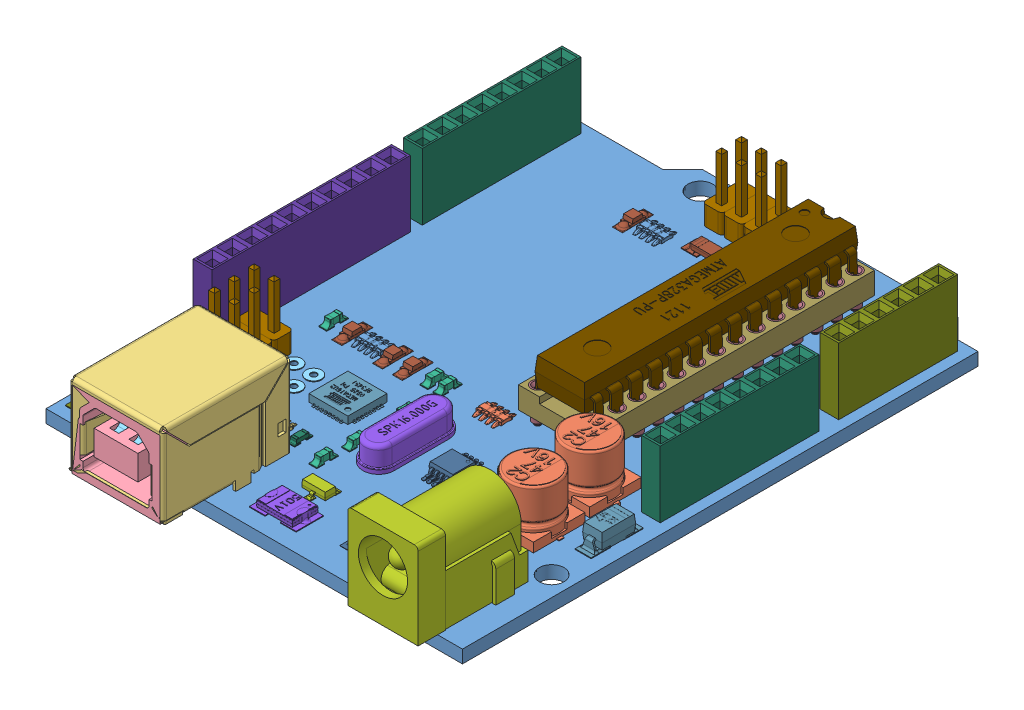
SolidWorks assembly Arduino Uno, configuration Default. Lengths in mm.
Overall size (53.34 15.65 74.93).
87 component instances, 35 part files, 133 mates.
Components (placement in the parent):
- unoboard blue-1: unoboard blue [Default] at origin size (53.34 1.65 68.58)
- 47uf CAP Dcase-1: 47uf CAP Dcase [Défaut] at (-9.4141 0 -18.4991) x (0 0 -1) z (1 0 0) size (6.6 6.6 7.25)
- USB type b-1: USB type b [Default] at (-38.02 0.83 6.35) size (13.72 15.2 16.5)
  - USB SHELL-1: USB SHELL [Default] at origin size (13.72 15.2 16.5)
  - USB core-1: USB core [Défaut] at origin size (11.3 10.68 15.75)
  - usb top contact-1: usb top contact [Default] at (1.25 5.69 0.01) size (1 9.67 13.76)
  - usb btm contact-1: usb btm contact [Default] at (1.25 4.01 -0.69) size (1 6.84 11.76)
  - usb btm contact-2: usb btm contact [Default] at (-1.25 4.01 -0.69) size (1 6.84 11.76)
  - usb top contact-2: usb top contact [Default] at (-1.25 5.69 0.01) size (1 9.67 13.76)
- power jack-1: power jack [Défaut] at (-7.675 0 2.5) size (9.45 15.2 14.2)
- 47uf CAP Dcase-2: 47uf CAP Dcase [Défaut] at (-9.4141 0.3 -25.7132) x (0 0 -1) z (1 0 0) size (6.6 6.6 7.25)
- crystal-1: crystal [Default] at (-26.162 0 -18.923) x (1 0 0) z (0 0 -1) size (4 5 11)
- 2pin_header__02-1: 2pin_header__02 [Default] at (-46.23 0 -15.75) size (5 11.75 2.54)
- nano - reg-1: nano - reg [Default] at (-17.399 0 -7.747) size (6.5 1.69 8.3)
- led 0805-1: led 0805 [Default] at (-34.29 0 -27.94) x (0 0 1) z (-1 0 0) size (4 0.86 1.35)
- 2pin_header__02-2: 2pin_header__02 [Default] at (-30.43 0 -64.91) x (0 0 1) z (-1 0 0) size (5 11.75 2.54)
- dip28-1: dip28 [Default] at (-16.383 1.5 -46.355) x (0 0 -1) z (1 0 0) size (35.48 7.37 10.1)
  - dip28-1: dip28 [Default] at origin size (35.48 2.8 10.1)
  - dip socket pin-1: dip socket pin [Default] at (16.51 2.8 -3.81) size (1.7 7.37 1.7)
  - dip socket pin-2: dip socket pin [Default] at (16.51 2.8 3.81) size (1.7 7.37 1.7)
  - dip socket pin-3: dip socket pin [Default] at (13.97 2.8 -3.81) size (1.7 7.37 1.7)
  - dip socket pin-4: dip socket pin [Default] at (13.97 2.8 3.81) size (1.7 7.37 1.7)
  - dip socket pin-5: dip socket pin [Default] at (11.43 2.8 -3.81) size (1.7 7.37 1.7)
  - dip socket pin-6: dip socket pin [Default] at (11.43 2.8 3.81) size (1.7 7.37 1.7)
  - dip socket pin-7: dip socket pin [Default] at (8.89 2.8 -3.81) size (1.7 7.37 1.7)
  - dip socket pin-8: dip socket pin [Default] at (8.89 2.8 3.81) size (1.7 7.37 1.7)
  - dip socket pin-9: dip socket pin [Default] at (6.35 2.8 -3.81) size (1.7 7.37 1.7)
  - dip socket pin-10: dip socket pin [Default] at (6.35 2.8 3.81) size (1.7 7.37 1.7)
  - dip socket pin-11: dip socket pin [Default] at (3.81 2.8 -3.81) size (1.7 7.37 1.7)
  - dip socket pin-12: dip socket pin [Default] at (3.81 2.8 3.81) size (1.7 7.37 1.7)
  - dip socket pin-13: dip socket pin [Default] at (1.27 2.8 -3.81) size (1.7 7.37 1.7)
  - dip socket pin-14: dip socket pin [Default] at (1.27 2.8 3.81) size (1.7 7.37 1.7)
  - dip socket pin-15: dip socket pin [Default] at (-1.27 2.8 -3.81) size (1.7 7.37 1.7)
  - dip socket pin-16: dip socket pin [Default] at (-1.27 2.8 3.81) size (1.7 7.37 1.7)
  - dip socket pin-17: dip socket pin [Default] at (-3.81 2.8 -3.81) size (1.7 7.37 1.7)
  - dip socket pin-18: dip socket pin [Default] at (-3.81 2.8 3.81) size (1.7 7.37 1.7)
  - dip socket pin-19: dip socket pin [Default] at (-6.35 2.8 -3.81) size (1.7 7.37 1.7)
  - dip socket pin-20: dip socket pin [Default] at (-6.35 2.8 3.81) size (1.7 7.37 1.7)
  - dip socket pin-21: dip socket pin [Default] at (-8.89 2.8 -3.81) size (1.7 7.37 1.7)
  - dip socket pin-22: dip socket pin [Default] at (-8.89 2.8 3.81) size (1.7 7.37 1.7)
  - dip socket pin-23: dip socket pin [Default] at (-11.43 2.8 -3.81) size (1.7 7.37 1.7)
  - dip socket pin-24: dip socket pin [Default] at (-11.43 2.8 3.81) size (1.7 7.37 1.7)
  - dip socket pin-25: dip socket pin [Default] at (-13.97 2.8 -3.81) size (1.7 7.37 1.7)
  - dip socket pin-26: dip socket pin [Default] at (-13.97 2.8 3.81) size (1.7 7.37 1.7)
  - dip socket pin-27: dip socket pin [Default] at (-16.51 2.8 -3.81) size (1.7 7.37 1.7)
  - dip socket pin-28: dip socket pin [Default] at (-16.51 2.8 3.81) size (1.7 7.37 1.7)
- 2pin_header__02-3: 2pin_header__02 [Default] at (-27.89 0 -64.91) x (0 0 1) z (-1 0 0) size (5 11.75 2.54)
- 2pin_header__02-4: 2pin_header__02 [Default] at (-25.35 0 -64.91) x (0 0 1) z (-1 0 0) size (5 11.75 2.54)
- 2pin_header__02-5: 2pin_header__02 [Default] at (-46.23 0 -18.29) size (5 11.75 2.54)
- 2pin_header__02-6: 2pin_header__02 [Default] at (-46.23 0 -20.83) size (5 11.75 2.54)
- atmega16u2-1: atmega16u2 [Default] at (-34.671 0.06 -20) x (1 0 0) z (0 0 -1) size (5.5 1.01 5.5)
- led 0805-2: led 0805 [Default] at (-36.83 0 -27.94) x (0 0 1) z (-1 0 0) size (4 0.86 1.35)
- led 0805-3: led 0805 [Default] at (-42.037 0 -27.94) x (0 0 1) z (-1 0 0) size (4 0.86 1.35)
- led 0805-4: led 0805 [Default] at (-36.576 0 -58.42) x (0 0 1) z (-1 0 0) size (4 0.86 1.35)
- 8 PORT HEADER-3: 8 PORT HEADER [Default] at (-50.8 0 -45.72) x (0 0 -1) z (1 0 0) size (20.32 10.51 2.41)
- 8 PORT HEADER-4: 8 PORT HEADER [Default] at (-2.54 0 -27.94) x (0 0 -1) z (1 0 0) size (20.32 10.51 2.41)
- 6 PORT HEADER-3: 6 PORT HEADER [Default] at (-2.54 0 -50.8) x (0 0 -1) z (1 0 0) size (15.24 10.51 2.41)
- 10 PORT HEADER-1: 10 PORT HEADER [Default] at (-50.8 0 -18.796) x (0 0 -1) z (1 0 0) size (25.4 10.51 2.41)
- ATMEL328P-1: ATMEL328P [Default] at (-16.383 4.3 -46.355) x (0 0 -1) z (1 0 0) size (35 7.27 7.87)
- 102 RESISTOR PACK-1: 102 RESISTOR PACK [Default] at (-33.782 0 -58.42) size (3.2 0.46 3)
- 102 RESISTOR PACK-2: 102 RESISTOR PACK [Default] at (-39.37 0 -27.94) size (3.2 0.46 3)
- 103 RESISTOR PACK-3: 103 RESISTOR PACK [Default] at (-23.876 0 -27.94) size (3.2 0.46 3)
- 220 RESISTOR PACK-1: 220 RESISTOR PACK [Default] at (-36.83 0 -12.827) size (3.2 0.46 3)
- 16mhz crystal - measured-1: 16mhz crystal - measured [Default] at (-24.892 0 -41.275) x (0 0 -1) z (1 0 0) size (3.4 0.8 2)
- PADS001-1: PADS001 [Default] at (-39.878 0.1 -18.288) x (-1 0 0) z (0 0 1) size (4.54 0.1 4.54)
- 603 cap on pad-1: 603 cap on pad [Défaut] at (-44.45 0 -27.94) x (0 0 -1) z (1 0 0) size (2.76 0.91 1.12)
- ssot3-1: ssot3 [Default] at (-26.5 0 -8.128) x (-1 0 0) z (0 0 -1) size (3 1.13 3.09)
- mf-msmf050-2-1: mf-msmf050-2 [Default] at (-26.5 0 -4.064) size (5.77 1.02 3.72)
- 603 cap on pad-2: 603 cap on pad [Défaut] at (-29.845 0 -27.94) x (0 0 -1) z (1 0 0) size (2.76 0.91 1.12)
- 603 cap on pad-3: 603 cap on pad [Défaut] at (-31.496 0 -27.94) x (0 0 -1) z (1 0 0) size (2.76 0.91 1.12)
- SOT23-5-1: SOT23-5 [Default] at (-15.24 0 -21.971) x (0 0 -1) z (1 0 0) size (3.7 1.4 2.9)
- 603 cap on pad-4: 603 cap on pad [Défaut] at (-15.24 0 -18.415) size (2.76 0.91 1.12)
- 603 cap on pad-5: 603 cap on pad [Défaut] at (-29.845 0 -12.065) x (0 0 1) z (-1 0 0) size (2.76 0.91 1.12)
- 603 cap on pad-6: 603 cap on pad [Défaut] at (-29.591 0 -22.352) x (0 0 1) z (-1 0 0) size (2.76 0.91 1.12)
- 603 cap on pad-7: 603 cap on pad [Défaut] at (-29.591 0 -16.002) x (0 0 1) z (-1 0 0) size (2.76 0.91 1.12)
- 603 cap on pad-8: 603 cap on pad [Défaut] at (-41.91 0 -12.7) x (0 0 1) z (-1 0 0) size (2.76 0.91 1.12)
- lp2985dgkr-1: lp2985dgkr [Default] at (-20.32 0 -19.05) x (0 0 -1) z (1 0 0) size (5.85 1.1 3)
- cd1206 diode-1: cd1206 diode [Default] at (-27.94 0 -59.436) x (0 0 -1) z (1 0 0) size (2.07 0.96 5)
- cd1206 diode-2: cd1206 diode [Default] at (-46.228 0 -13.081) x (0 0 1) z (-1 0 0) size (2.07 0.96 5)
- 603 resistor-1: 603 resistor [Default] at (-29.591 0 -19.05) x (0 0 1) z (-1 0 0) size (2.36 0.61 1.03)
- blm21-1: blm21 [Défaut] at (-45.085 0 -7.62) x (0 0 -1) z (1 0 0) size (2.76 0.96 1.33)
- m7 diode-1: m7 diode [Default] at (-2.794 0 -21.59) x (0 0 -1) z (1 0 0) size (6.66 2.35 2.5)
- MLC0603-1: MLC0603 [Default] at (-33.655 0 -12.827) x (0 0 -1) z (1 0 0) size (2.36 0.6 1.03)
- MLC0603-2: MLC0603 [Default] at (-39.37 0 -12.827) x (0 0 -1) z (1 0 0) size (2.36 0.6 1.03)
- RESET BUTTON-1: RESET BUTTON [Default] at (-49.403 0 -6.35) size (6.2 3.1 9.6)
  - RESET CORE-1: RESET CORE [Default] at (0 0.1 0) x (-1 0 0) z (0 0 -1) size (6.2 3.1 9.6)
  - RESET-1: RESET [Default] at (0 0.1 0) x (0 0 1) z (-1 0 0) size (7.3 2 6.2)
Mates (geometry in assembly coordinates):
- Distance1: distance = 2.5 mm aligned: plane of power jack-1 through (-7.675 0 2.5) normal (0 0 1); plane of unoboard blue-1 through (0 0 0) normal (0 0 1)
- Coincident2: coincident aligned: plane of unoboard blue-1 through (0 0 0) normal (0 1 0); plane of power jack-1 through (-7.675 0 2.5) normal (0 1 0)
- Coincident3: coincident anti-aligned: plane of unoboard blue-1 through (0 0 0) normal (0 1 0); plane of USB type b-1/USB core-1 through (-38.02 0 6.35) normal (0 -1 0)
- Distance2: distance = 6.35 mm aligned: plane of USB type b-1/USB SHELL-1 through (-38.02 0.83 6.35) normal (0 0 1); plane of unoboard blue-1 through (0 0 0) normal (0 0 1)
- Coincident5: coincident aligned: plane of unoboard blue-1 through (0 0 0) normal (0 1 0); plane of 47uf CAP Dcase-1 through (-9.4141 0 -18.4991) normal (0 1 0)
- Parallel1: parallel anti-aligned: plane of unoboard blue-1 through (0 0 0) normal (0 0 1); plane of 47uf CAP Dcase-1 through (-9.4141 0 -18.4991) normal (0 0 -1)
- Coincident7: coincident aligned: plane of 47uf CAP Dcase-2 through (-6.1141 1.5 -22.4132) normal (1 0 0); plane of 47uf CAP Dcase-1 through (-6.1141 1.2 -15.1991) normal (1 0 0)
- Coincident8: coincident anti-aligned: plane of unoboard blue-1 through (0 0 0) normal (0 1 0); plane of 47uf CAP Dcase-2 through (-9.4141 0 -25.7132) normal (0 -1 0)
- Distance3: distance = 3.175 mm aligned: plane of power jack-1 through (-3.175 10.5 -1) normal (1 0 0); plane of unoboard blue-1 through (0 -1.65 0) normal (1 0 0)
- Distance4: distance = 32 mm aligned: plane of USB type b-1/USB SHELL-1 through (-32 0.83 6.35) normal (1 0 0); plane of unoboard blue-1 through (0 -1.65 0) normal (1 0 0)
- Coincident11: coincident anti-aligned: plane of unoboard blue-1 through (0 0 0) normal (0 1 0); plane of crystal-1 through (-26.162 0 -22.423) normal (0 -1 0)
- Concentric1: concentric aligned: cylinder of unoboard blue-1 through (-26.162 -10 -16.383) axis (0 1 0) radius 0.5; cylinder of crystal-1 through (-26.162 -2 -16.383) axis (0 1 0) radius 0.4
- Concentric2: concentric aligned: cylinder of unoboard blue-1 through (-26.162 -10 -21.463) axis (0 1 0) radius 0.5; cylinder of crystal-1 through (-26.162 -2 -21.463) axis (0 1 0) radius 0.4
- Coincident12: coincident anti-aligned: plane of unoboard blue-1 through (0 0 0) normal (0 1 0); plane of 2pin_header__02-1 through (-44.23 0 -14.98) normal (0 -1 0)
- Distance5: distance = 15.75 mm aligned: plane of 2pin_header__02-1 through (-46.23 0 -15.75) normal (0 0 1); plane of assembly through (0 0 0) normal (0 0 1)
- Distance6: distance = 46.23 mm aligned: plane of 2pin_header__02-1 through (-46.23 0 -15.75) normal (1 0 0); plane of assembly through (0 0 0) normal (1 0 0)
- Coincident15: coincident anti-aligned: plane of unoboard blue-1 through (0 0 0) normal (0 1 0); plane of 2pin_header__02-2 through (-31.2 0 -62.91) normal (0 -1 0)
- Distance7: distance = 64.91 mm aligned: plane of 2pin_header__02-2 through (-30.43 0 -64.91) normal (0 0 1); plane of assembly through (0 0 0) normal (0 0 1)
- Distance8: distance = 30.43 mm anti-aligned: plane of 2pin_header__02-2 through (-30.43 0 -64.91) normal (-1 0 0); plane of assembly through (0 0 0) normal (1 0 0)
- Coincident19: coincident anti-aligned: plane of unoboard blue-1 through (0 0 0) normal (0 1 0); plane of nano - reg-1 through (-17.399 0 -7.747) normal (0 -1 0)
- Concentric3: concentric aligned: cylinder of unoboard blue-1 through (-20.193 -10 -62.865) axis (0 1 0) radius 0.4; cylinder of dip28-1/dip socket pin-1 through (-20.193 33.2926 -62.865) axis (0 1 0) radius 0.25
- Concentric4: concentric aligned: cylinder of unoboard blue-1 through (-12.573 -10 -29.845) axis (0 1 0) radius 0.4; cylinder of dip28-1/dip socket pin-28 through (-12.573 33.2926 -29.845) axis (0 1 0) radius 0.25
- Distance9: distance = 1.5 mm anti-aligned: plane of dip28-1/dip28-1 through (-11.333 1.5 -64.095) normal (0 -1 0); plane of unoboard blue-1 through (0 0 0) normal (0 1 0)
- Coincident21: coincident anti-aligned: plane of unoboard blue-1 through (0 0 0) normal (0 1 0); plane of atmega16u2-1 through (-34.671 0 -20) normal (0 -1 0)
- Distance10: distance = 20 mm anti-aligned: plane of atmega16u2-1 through (-34.671 0.06 -20) normal (0 0 -1); plane of unoboard blue-1 through (0 0 0) normal (0 0 1)
- Distance11: distance = 34.671 mm aligned: plane of atmega16u2-1 through (-34.671 0.06 -20) normal (1 0 0); plane of unoboard blue-1 through (0 0 0) normal (1 0 0)
- Coincident25: coincident anti-aligned: plane of unoboard blue-1 through (0 0 0) normal (0 1 0); plane of led 0805-1 through (-34.29 0 -28.94) normal (0 -1 0)
- Distance12: distance = 34.29 mm anti-aligned: plane of led 0805-1 through (-34.29 0 -27.94) normal (-1 0 0); plane of unoboard blue-1 through (0 0 0) normal (1 0 0)
- Distance13: distance = 27.94 mm aligned: plane of led 0805-1 through (-34.29 0 -27.94) normal (0 0 1); plane of unoboard blue-1 through (0 0 0) normal (0 0 1)
- Coincident28: coincident aligned: plane of led 0805-2 through (-36.83 0 -28.94) normal (0 -1 0); plane of led 0805-3 through (-42.037 0 -28.94) normal (0 -1 0)
- Coincident29: coincident aligned: plane of led 0805-1 through (-34.29 0 -27.94) normal (0 0 1); plane of led 0805-2 through (-36.83 0 -27.94) normal (0 0 1)
- Coincident30: coincident aligned: plane of led 0805-1 through (-34.29 0 -27.94) normal (0 0 1); plane of led 0805-3 through (-42.037 0 -27.94) normal (0 0 1)
- Distance14: distance = 2.54 mm aligned: plane of led 0805-2 through (-36.83 0 -27.94) normal (-1 0 0); plane of led 0805-1 through (-34.29 0 -27.94) normal (-1 0 0)
- Coincident32: coincident anti-aligned: plane of unoboard blue-1 through (0 0 0) normal (0 1 0); plane of led 0805-2 through (-36.83 0 -28.94) normal (0 -1 0)
- Distance15: distance = 42.037 mm anti-aligned: plane of led 0805-3 through (-42.037 0 -27.94) normal (-1 0 0); plane of unoboard blue-1 through (0 0 0) normal (1 0 0)
- Coincident34: coincident anti-aligned: plane of unoboard blue-1 through (0 0 0) normal (0 1 0); plane of led 0805-4 through (-36.576 0 -59.42) normal (0 -1 0)
- Distance16: distance = 36.576 mm anti-aligned: plane of led 0805-4 through (-36.576 0 -58.42) normal (-1 0 0); plane of unoboard blue-1 through (0 0 0) normal (1 0 0)
- Distance17: distance = 58.42 mm aligned: plane of led 0805-4 through (-36.576 0 -58.42) normal (0 0 1); plane of unoboard blue-1 through (0 0 0) normal (0 0 1)
- Coincident37: coincident aligned: plane of unoboard blue-1 through (0 0 0) normal (0 1 0); plane of 8 PORT HEADER-4 through (-2.54 0 -27.94) normal (0 1 0)
- Coincident38: coincident aligned: plane of unoboard blue-1 through (0 0 0) normal (0 1 0); plane of 8 PORT HEADER-3 through (-50.8 0 -45.72) normal (0 1 0)
- Parallel2: parallel aligned: plane of unoboard blue-1 through (0 0 0) normal (1 0 0); plane of 8 PORT HEADER-4 through (-2.54 0 -27.94) normal (1 0 0)
- Parallel3: parallel aligned: plane of unoboard blue-1 through (0 0 0) normal (1 0 0); plane of 8 PORT HEADER-3 through (-50.8 0 -45.72) normal (1 0 0)
- Concentric5: concentric aligned: cylinder of unoboard blue-1 through (-2.54 -1.65 -27.94) axis (0 1 0) radius 0.4; line of 8 PORT HEADER-4 through (-2.54 -2.5255 -27.94) axis (0 1 0)
- Concentric6: concentric aligned: cylinder of unoboard blue-1 through (-50.8 -1.65 -45.72) axis (0 1 0) radius 0.4; line of 8 PORT HEADER-3 through (-50.8 -2.5255 -45.72) axis (0 1 0)
- Coincident43: coincident aligned: plane of unoboard blue-1 through (0 0 0) normal (0 1 0); plane of 10 PORT HEADER-1 through (-50.8 0 -18.796) normal (0 1 0)
- Coincident44: coincident aligned: plane of unoboard blue-1 through (0 0 0) normal (0 1 0); plane of 6 PORT HEADER-3 through (-2.54 0 -50.8) normal (0 1 0)
- Parallel4: parallel aligned: plane of unoboard blue-1 through (0 0 0) normal (1 0 0); plane of 6 PORT HEADER-3 through (-2.54 0 -50.8) normal (1 0 0)
- Parallel5: parallel aligned: plane of unoboard blue-1 through (0 0 0) normal (1 0 0); plane of 10 PORT HEADER-1 through (-50.8 0 -18.796) normal (1 0 0)
- Concentric7: concentric aligned: cylinder of unoboard blue-1 through (-50.8 -1.65 -18.796) axis (0 1 0) radius 0.4; line of 10 PORT HEADER-1 through (-50.8 -2.5255 -18.796) axis (0 1 0)
- Concentric9: concentric aligned: cylinder of unoboard blue-1 through (-2.54 -1.65 -50.8) axis (0 1 0) radius 0.4; line of 6 PORT HEADER-3 through (-2.54 -2.5255 -50.8) axis (0 1 0)
- Coincident50: coincident aligned: plane of dip28-1/dip28-1 through (-16.383 1.5 -46.355) normal (0 0 -1); plane of ATMEL328P-1 through (-16.383 4.3 -46.355) normal (0 0 -1)
- Coincident51: coincident aligned: plane of dip28-1 through (-16.383 1.5 -46.355) normal (1 0 0); plane of ATMEL328P-1 through (-16.383 4.3 -46.355) normal (1 0 0)
- Coincident52: coincident aligned: plane of dip28-1/dip28-1 through (-11.333 4.3 -64.095) normal (0 1 0); plane of ATMEL328P-1 through (-16.383 4.3 -46.355) normal (0 1 0)
- Distance18: distance = 7.747 mm: plane of nano - reg-1 through (-17.399 0 -7.747) normal (0 0 1); line of unoboard blue-1 through (0 53.34 -53.34) axis (0 0 1)
- Distance19: distance = 17.399 mm aligned: plane of nano - reg-1 through (-17.399 0 -7.747) normal (1 0 0); plane of unoboard blue-1 through (0 0 0) normal (1 0 0)
- Coincident55: coincident anti-aligned: plane of unoboard blue-1 through (0 0 0) normal (0 1 0); plane of 102 RESISTOR PACK-1 through (-33.982 0 -59.12) normal (0 -1 0)
- Distance20: distance = 33.782 mm aligned: plane of 102 RESISTOR PACK-1 through (-33.782 0 -58.42) normal (1 0 0); plane of unoboard blue-1 through (0 0 0) normal (1 0 0)
- Distance21: distance = 58.42 mm aligned: plane of 102 RESISTOR PACK-1 through (-33.782 0 -58.42) normal (0 0 1); plane of unoboard blue-1 through (0 0 0) normal (0 0 1)
- Coincident58: coincident aligned: plane of 102 RESISTOR PACK-2 through (-39.37 0 -27.94) normal (0 1 0); plane of 103 RESISTOR PACK-3 through (-23.876 0 -27.94) normal (0 1 0)
- Coincident59: coincident aligned: plane of unoboard blue-1 through (0 0 0) normal (0 1 0); plane of 103 RESISTOR PACK-3 through (-23.876 0 -27.94) normal (0 1 0)
- Coincident60: coincident aligned: plane of 102 RESISTOR PACK-2 through (-39.37 0 -27.94) normal (0 0 1); plane of 103 RESISTOR PACK-3 through (-23.876 0 -27.94) normal (0 0 1)
- Distance22: distance = 23.876 mm aligned: plane of 103 RESISTOR PACK-3 through (-23.876 0 -27.94) normal (1 0 0); plane of unoboard blue-1 through (0 0 0) normal (1 0 0)
- Distance23: distance = 39.37 mm aligned: plane of 102 RESISTOR PACK-2 through (-39.37 0 -27.94) normal (1 0 0); plane of unoboard blue-1 through (0 0 0) normal (1 0 0)
- Distance24: distance = 27.94 mm aligned: plane of 102 RESISTOR PACK-2 through (-39.37 0 -27.94) normal (0 0 1); plane of unoboard blue-1 through (0 0 0) normal (0 0 1)
- Distance25: distance = 12.827 mm aligned: plane of 220 RESISTOR PACK-1 through (-36.83 0 -12.827) normal (0 0 1); plane of unoboard blue-1 through (0 0 0) normal (0 0 1)
- Distance26: distance = 36.83 mm aligned: plane of 220 RESISTOR PACK-1 through (-36.83 0 -12.827) normal (1 0 0); plane of unoboard blue-1 through (0 0 0) normal (1 0 0)
- Coincident66: coincident aligned: plane of unoboard blue-1 through (0 0 0) normal (0 1 0); plane of 220 RESISTOR PACK-1 through (-36.83 0 -12.827) normal (0 1 0)
- Coincident67: coincident anti-aligned: plane of unoboard blue-1 through (0 0 0) normal (0 1 0); plane of 16mhz crystal - measured-1 through (-24.892 0 -41.275) normal (0 -1 0)
- Distance27: distance = 41.275 mm anti-aligned: plane of 16mhz crystal - measured-1 through (-24.892 0 -41.275) normal (0 0 -1); plane of unoboard blue-1 through (0 0 0) normal (0 0 1)
- Distance28: distance = 24.892 mm aligned: plane of 16mhz crystal - measured-1 through (-24.892 0 -41.275) normal (1 0 0); plane of unoboard blue-1 through (0 0 0) normal (1 0 0)
- Coincident70: coincident anti-aligned: plane of unoboard blue-1 through (0 0 0) normal (0 1 0); plane of PADS001-1 through (-42.418 0 -18.288) normal (0 -1 0)
- Distance29: distance = 18.288 mm aligned: plane of PADS001-1 through (-39.878 0.1 -18.288) normal (0 0 1); plane of unoboard blue-1 through (0 0 0) normal (0 0 1)
- Distance30: distance = 39.878 mm anti-aligned: plane of PADS001-1 through (-39.878 0.1 -18.288) normal (-1 0 0); plane of unoboard blue-1 through (0 0 0) normal (1 0 0)
- Distance31: distance = 4.064 mm aligned: plane of mf-msmf050-2-1 through (-26.5 0 -4.064) normal (0 0 1); plane of unoboard blue-1 through (0 0 0) normal (0 0 1)
- Distance32: distance = 26.5 mm aligned: plane of mf-msmf050-2-1 through (-26.5 0 -4.064) normal (1 0 0); plane of unoboard blue-1 through (0 0 0) normal (1 0 0)
- Coincident72: coincident aligned: plane of unoboard blue-1 through (0 0 0) normal (0 1 0); plane of mf-msmf050-2-1 through (-26.5 0 -4.064) normal (0 1 0)
- Distance33: distance = 8.128 mm anti-aligned: plane of unoboard blue-1 through (0 0 0) normal (0 0 1); plane of ssot3-1 through (-26.5 0 -8.128) normal (0 0 -1)
- Coincident74: coincident anti-aligned: plane of ssot3-1 through (-26.5 0 -8.128) normal (-1 0 0); plane of mf-msmf050-2-1 through (-26.5 0 -4.064) normal (1 0 0)
- Coincident75: coincident aligned: plane of unoboard blue-1 through (0 0 0) normal (0 1 0); plane of ssot3-1 through (-26.5 0 -8.128) normal (0 1 0)
- Coincident76: coincident anti-aligned: plane of led 0805-1 through (-34.29 0 -27.94) normal (0 0 1); plane of 603 cap on pad-1 through (-44.45 0 -27.94) normal (0 0 -1)
- Coincident77: coincident aligned: plane of unoboard blue-1 through (0 0 0) normal (0 1 0); plane of 603 cap on pad-1 through (-44.45 0 -27.94) normal (0 1 0)
- Distance34: distance = 44.45 mm aligned: plane of 603 cap on pad-1 through (-44.45 0 -27.94) normal (1 0 0); plane of unoboard blue-1 through (0 0 0) normal (1 0 0)
- Coincident79: coincident aligned: plane of 603 cap on pad-2 through (-29.845 0 -27.94) normal (0 1 0); plane of 603 cap on pad-3 through (-31.496 0 -27.94) normal (0 1 0)
- Coincident80: coincident aligned: plane of 603 cap on pad-2 through (-29.845 0 -27.94) normal (0 0 -1); plane of 603 cap on pad-3 through (-31.496 0 -27.94) normal (0 0 -1)
- Coincident81: coincident aligned: plane of unoboard blue-1 through (0 0 0) normal (0 1 0); plane of 603 cap on pad-2 through (-29.845 0 -27.94) normal (0 1 0)
- Coincident82: coincident aligned: plane of 603 cap on pad-1 through (-44.45 0 -27.94) normal (0 0 -1); plane of 603 cap on pad-2 through (-29.845 0 -27.94) normal (0 0 -1)
- Distance36: distance = 29.845 mm aligned: plane of 603 cap on pad-2 through (-29.845 0 -27.94) normal (1 0 0); plane of unoboard blue-1 through (0 0 0) normal (1 0 0)
- Distance37: distance = 31.496 mm aligned: plane of 603 cap on pad-3 through (-31.496 0 -27.94) normal (1 0 0); plane of unoboard blue-1 through (0 0 0) normal (1 0 0)
- Distance38: distance = 15.24 mm aligned: plane of unoboard blue-1 through (0 0 0) normal (1 0 0); plane of SOT23-5-1 through (-15.24 0 -21.971) normal (1 0 0)
- Distance39: distance = 21.971 mm anti-aligned: plane of SOT23-5-1 through (-15.24 0 -21.971) normal (0 0 -1); plane of unoboard blue-1 through (0 0 0) normal (0 0 1)
- Coincident88: coincident aligned: plane of unoboard blue-1 through (0 0 0) normal (0 1 0); plane of SOT23-5-1 through (-15.24 0 -21.971) normal (0 1 0)
- Distance40: distance = 18.415 mm aligned: plane of 603 cap on pad-4 through (-15.24 0 -18.415) normal (0 0 1); plane of unoboard blue-1 through (0 0 0) normal (0 0 1)
- Distance41: distance = 15.24 mm aligned: plane of 603 cap on pad-4 through (-15.24 0 -18.415) normal (1 0 0); plane of unoboard blue-1 through (0 0 0) normal (1 0 0)
- Coincident91: coincident aligned: plane of unoboard blue-1 through (0 0 0) normal (0 1 0); plane of 603 cap on pad-4 through (-15.24 0 -18.415) normal (0 1 0)
- Coincident92: coincident aligned: plane of unoboard blue-1 through (0 0 0) normal (0 1 0); plane of 603 cap on pad-7 through (-29.591 0 -16.002) normal (0 1 0)
- Coincident93: coincident aligned: plane of unoboard blue-1 through (0 0 0) normal (0 1 0); plane of 603 cap on pad-6 through (-29.591 0 -22.352) normal (0 1 0)
- Coincident94: coincident aligned: plane of 603 cap on pad-5 through (-29.845 0 -12.065) normal (0 1 0); plane of unoboard blue-1 through (0 0 0) normal (0 1 0)
- Coincident95: coincident aligned: plane of 603 cap on pad-8 through (-41.91 0 -12.7) normal (0 1 0); plane of unoboard blue-1 through (0 0 0) normal (0 1 0)
- Coincident96: coincident aligned: plane of 603 cap on pad-7 through (-29.591 0 -16.002) normal (-1 0 0); plane of 603 cap on pad-6 through (-29.591 0 -22.352) normal (-1 0 0)
- Distance42: distance = 29.591 mm anti-aligned: plane of 603 cap on pad-7 through (-29.591 0 -16.002) normal (-1 0 0); plane of unoboard blue-1 through (0 0 0) normal (1 0 0)
- Distance43: distance = 22.352 mm: plane of 603 cap on pad-6 through (-29.591 0 -22.352) normal (0 0 1); line of unoboard blue-1 through (0 53.34 -53.34) axis (0 0 1)
- Distance44: distance = 16.002 mm aligned: plane of 603 cap on pad-7 through (-29.591 0 -16.002) normal (0 0 1); plane of unoboard blue-1 through (0 0 0) normal (0 0 1)
- Distance45: distance = 29.845 mm anti-aligned: plane of 603 cap on pad-5 through (-29.845 0 -12.065) normal (-1 0 0); plane of unoboard blue-1 through (0 0 0) normal (1 0 0)
- Distance46: distance = 12.065 mm aligned: plane of 603 cap on pad-5 through (-29.845 0 -12.065) normal (0 0 1); plane of unoboard blue-1 through (0 0 0) normal (0 0 1)
- Distance47: distance = 41.91 mm anti-aligned: plane of 603 cap on pad-8 through (-41.91 0 -12.7) normal (-1 0 0); plane of unoboard blue-1 through (0 0 0) normal (1 0 0)
- Distance48: distance = 12.7 mm aligned: plane of 603 cap on pad-8 through (-41.91 0 -12.7) normal (0 0 1); plane of unoboard blue-1 through (0 0 0) normal (0 0 1)
- Distance49: distance = 20.32 mm aligned: plane of lp2985dgkr-1 through (-20.32 0 -19.05) normal (1 0 0); plane of unoboard blue-1 through (0 0 0) normal (1 0 0)
- Distance50: distance = 19.05 mm anti-aligned: plane of lp2985dgkr-1 through (-20.32 0 -19.05) normal (0 0 -1); plane of unoboard blue-1 through (0 0 0) normal (0 0 1)
- Coincident99: coincident aligned: plane of unoboard blue-1 through (0 0 0) normal (0 1 0); plane of lp2985dgkr-1 through (-20.32 0 -19.05) normal (0 1 0)
- Distance51: distance = 27.94 mm aligned: plane of cd1206 diode-1 through (-27.94 0 -59.436) normal (1 0 0); plane of unoboard blue-1 through (0 0 0) normal (1 0 0)
- Distance52: distance = 59.436 mm anti-aligned: plane of cd1206 diode-1 through (-27.94 0 -59.436) normal (0 0 -1); plane of unoboard blue-1 through (0 0 0) normal (0 0 1)
- Coincident102: coincident aligned: plane of unoboard blue-1 through (0 0 0) normal (0 1 0); plane of cd1206 diode-1 through (-27.94 0 -59.436) normal (0 1 0)
- Distance53: distance = 46.228 mm anti-aligned: plane of cd1206 diode-2 through (-46.228 0 -13.081) normal (-1 0 0); plane of unoboard blue-1 through (0 0 0) normal (1 0 0)
- Distance54: distance = 13.081 mm aligned: plane of unoboard blue-1 through (0 0 0) normal (0 0 1); plane of cd1206 diode-2 through (-46.228 0 -13.081) normal (0 0 1)
- Coincident105: coincident aligned: plane of unoboard blue-1 through (0 0 0) normal (0 1 0); plane of cd1206 diode-2 through (-46.228 0 -13.081) normal (0 1 0)
- Distance55: distance = 29.591 mm anti-aligned: plane of 603 resistor-1 through (-29.591 0 -19.05) normal (-1 0 0); plane of unoboard blue-1 through (0 0 0) normal (1 0 0)
- Distance56: distance = 19.05 mm aligned: plane of 603 resistor-1 through (-29.591 0 -19.05) normal (0 0 1); plane of unoboard blue-1 through (0 0 0) normal (0 0 1)
- Coincident108: coincident aligned: plane of unoboard blue-1 through (0 0 0) normal (0 1 0); plane of 603 resistor-1 through (-29.591 0 -19.05) normal (0 1 0)
- Distance57: distance = 7.62 mm anti-aligned: plane of blm21-1 through (-45.085 0 -7.62) normal (0 0 -1); plane of unoboard blue-1 through (0 0 0) normal (0 0 1)
- Distance58: distance = 45.085 mm aligned: plane of blm21-1 through (-45.085 0 -7.62) normal (1 0 0); plane of unoboard blue-1 through (0 0 0) normal (1 0 0)
- Distance59: distance = 21.59 mm anti-aligned: plane of m7 diode-1 through (-2.794 0 -21.59) normal (0 0 -1); plane of unoboard blue-1 through (0 0 0) normal (0 0 1)
- Distance60: distance = 2.794 mm aligned: plane of m7 diode-1 through (-2.794 0 -21.59) normal (1 0 0); plane of unoboard blue-1 through (0 0 0) normal (1 0 0)
- Coincident113: coincident aligned: plane of unoboard blue-1 through (0 0 0) normal (0 1 0); plane of m7 diode-1 through (-2.794 0 -21.59) normal (0 1 0)
- Coincident114: coincident anti-aligned: plane of 220 RESISTOR PACK-1 through (-36.83 0 -12.827) normal (0 0 1); plane of MLC0603-1 through (-33.655 0 -12.827) normal (0 0 -1)
- Distance61: distance = 33.655 mm aligned: plane of MLC0603-1 through (-33.655 0 -12.827) normal (1 0 0); plane of unoboard blue-1 through (0 0 0) normal (1 0 0)
- Coincident115: coincident aligned: plane of unoboard blue-1 through (0 0 0) normal (0 1 0); plane of MLC0603-1 through (-33.655 0 -12.827) normal (0 1 0)
- Coincident116: coincident aligned: plane of unoboard blue-1 through (0 0 0) normal (0 1 0); plane of blm21-1 through (-45.085 0 -7.62) normal (0 1 0)
- Coincident117: coincident anti-aligned: plane of 220 RESISTOR PACK-1 through (-36.83 0 -12.827) normal (0 0 1); plane of MLC0603-2 through (-39.37 0 -12.827) normal (0 0 -1)
- Coincident118: coincident aligned: plane of unoboard blue-1 through (0 0 0) normal (0 1 0); plane of MLC0603-2 through (-39.37 0 -12.827) normal (0 1 0)
- Distance62: distance = 39.37 mm aligned: plane of MLC0603-2 through (-39.37 0 -12.827) normal (1 0 0); plane of unoboard blue-1 through (0 0 0) normal (1 0 0)
- Distance63: distance = 49.403 mm aligned: plane of RESET BUTTON-1 through (-49.403 0 -6.35) normal (1 0 0); plane of unoboard blue-1 through (0 0 0) normal (1 0 0)
- Distance64: distance = 6.35 mm aligned: plane of RESET BUTTON-1; plane of unoboard blue-1 through (0 0 0) normal (0 0 1)
- Coincident122: coincident aligned: plane of unoboard blue-1 through (0 0 0) normal (0 1 0); plane of RESET BUTTON-1 through (-49.403 0 -6.35) normal (0 1 0)
